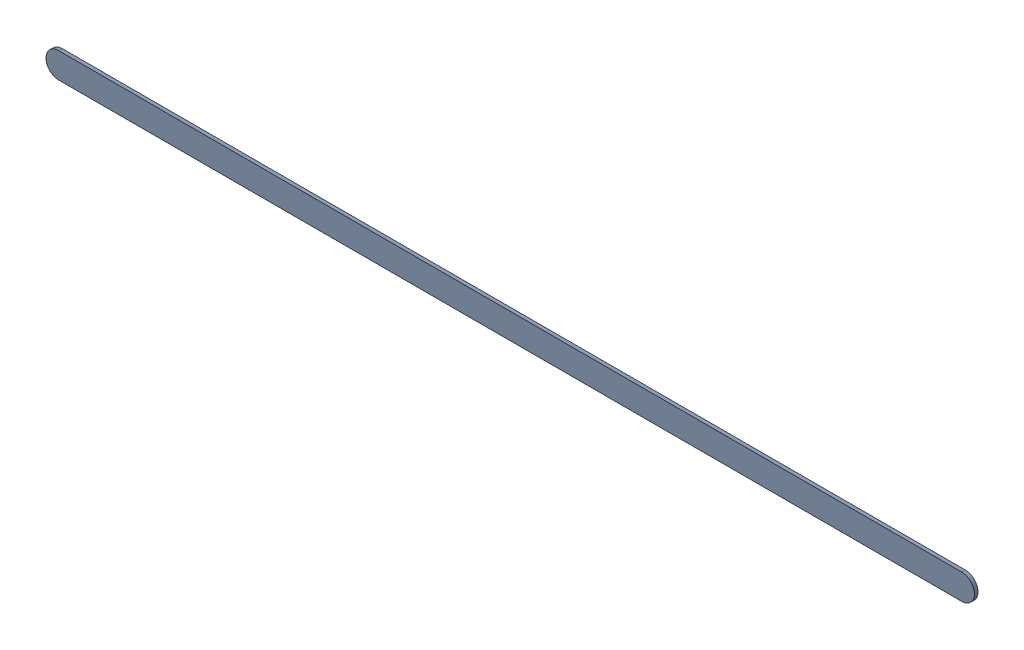
SolidWorks assembly Track (8.3mm,50.7mm)(17.308mm,50.7mm) on Bottom Layer, configuration Predeterminado. Lengths in mm.
Overall size (9.26 0.25 0.04).
2 component instances, 1 part files, 0 mates.
Components (placement in the parent):
- Track (8.3mm,50.7mm)(17.308mm,50.7mm) on Bottom Layer-1-1: Track (8.3mm,50.7mm)(17.308mm,50.7mm) on Bottom Layer-1 [Predeterminado] at (-68.317 -44.187 -0.4013) size (9.26 0.25 0.04)
  - Track (8.3mm,50.7mm)(17.308mm,50.7mm) on Bottom Layer-Part-1-1: Track (8.3mm,50.7mm)(17.308mm,50.7mm) on Bottom Layer-Part-1 [Predeterminado] at origin size (9.26 0.25 0.04)
